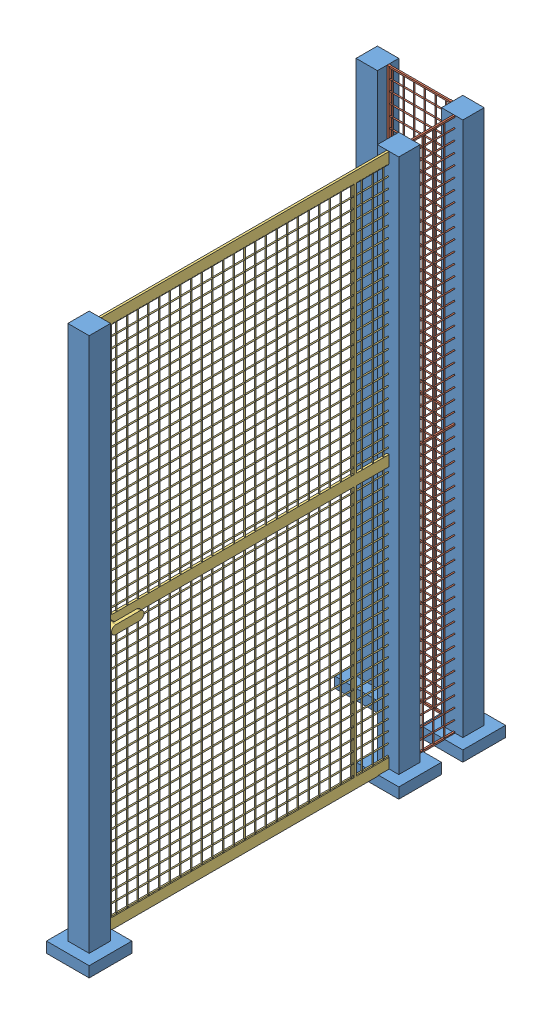
SolidWorks assembly bariera_porta_angolo, configuration Default. Lengths in mm.
Overall size (600 2555 1950).
7 component instances, 3 part files, 19 mates.
Components (placement in the parent):
- palo_barriera-1: palo_barriera [Default] at origin size (200 2555 200)
- palo_barriera-2: palo_barriera [Default] at (0 0 1750) size (200 2555 200)
- palo_barriera-3: palo_barriera [Default] at (0 0 300) size (200 2555 200)
- palo_barriera-4: palo_barriera [Default] at (-400 0 0) size (200 2555 200)
- rete 300-1: rete 300 [Default] at (-77.5 2551.25 0) x (-1 0 0) z (0 -1 0) size (300 10 2507.5)
- rete 300-2: rete 300 [Default] at (10 51.249 297.5) x (0 0 -1) z (0 1 0) size (300 10 2507.5)
- rete2m-1: rete2m [Default] at (0 51.25 1672.5) x (0 0 -1) z (0 1 0) size (1350 55 2507.5)
Mates (geometry in assembly coordinates):
- Coincidente1: coordinate: point of palo_barriera-1
- Distanza1: distance = 1750 mm aligned: plane of palo_barriera-1 through (0 0 0) normal (0 0 1); plane of palo_barriera-2 through (0 0 1750) normal (0 0 1)
- Coincidente3: coincident aligned: plane of palo_barriera-1 through (-50 2550 -50) normal (-1 0 0); plane of palo_barriera-2 through (-50 2550 1700) normal (-1 0 0)
- Coincidente4: coincident aligned: plane of palo_barriera-1 through (0 2555 0) normal (0 1 0); plane of palo_barriera-2 through (0 2555 1750) normal (0 1 0)
- Coincidente5: coincident aligned: plane of palo_barriera-1 through (50 2550 -50) normal (1 0 0); plane of palo_barriera-3 through (50 2550 250) normal (1 0 0)
- Coincidente6: coincident aligned: plane of palo_barriera-1 through (0 2555 0) normal (0 1 0); plane of palo_barriera-3 through (0 2555 300) normal (0 1 0)
- Distanza2: distance = 300 mm aligned: plane of palo_barriera-1 through (0 0 0) normal (0 0 1); plane of palo_barriera-3 through (0 0 300) normal (0 0 1)
- Coincidente8: coincident aligned: plane of palo_barriera-1 through (0 2555 0) normal (0 1 0); plane of palo_barriera-4 through (-400 2555 0) normal (0 1 0)
- Coincidente9: coincident aligned: plane of palo_barriera-1 through (-50 2550 -50) normal (0 0 -1); plane of palo_barriera-4 through (-450 2550 -50) normal (0 0 -1)
- Distanza4: distance = 400 mm aligned: plane of palo_barriera-4 through (-400 0 0) normal (1 0 0); plane of palo_barriera-1 through (0 0 0) normal (1 0 0)
- Coincidente12: coincident aligned: plane of palo_barriera-1 through (0 2555 0) normal (0 1 0); plane of rete 300-1 through (-1010.6066 2555 -3.75) normal (0 1 0)
- Distanza5: distance = 45 mm aligned: plane of rete 300-1 through (-340 2569.1421 -5) normal (0 0 -1); plane of palo_barriera-4 through (-450 2550 -50) normal (0 0 -1)
- Coincidente14: coincident anti-aligned: plane of palo_barriera-4 through (-350 2550 -50) normal (1 0 0); plane of rete 300-1 through (-350 3232.2262 -24.5677) normal (-1 0 0)
- Distanza7: distance = 45 mm anti-aligned: plane of palo_barriera-3 through (50 2550 250) normal (1 0 0); plane of rete 300-2 through (5 33.3569 35) normal (-1 0 0)
- Distanza6: distance = 25 mm anti-aligned: plane of palo_barriera-1 through (-50 2550 50) normal (0 0 1); plane of rete 300-2 through (-14.5677 -629.7272 25) normal (0 0 -1)
- Distanza8: distance = 0.001 mm aligned: plane of palo_barriera-3 through (0 2555 300) normal (0 1 0); plane of rete 300-2 through (6.25 2554.999 -635.6066) normal (0 1 0)
- Coincidente18: coincident anti-aligned: plane of palo_barriera-3 through (-50 2550 350) normal (0 0 1); plane of rete2m-1 through (-171.1689 41.25 350) normal (0 0 -1)
- Coincidente19: coincident aligned: plane of palo_barriera-3 through (0 2555 300) normal (0 1 0); plane of rete2m-1 through (-3.75 2555 -710.6066) normal (0 1 0)
- Distanza9: distance = 45 mm aligned: plane of rete2m-1 through (5 2569.1421 1700) normal (1 0 0); plane of palo_barriera-3 through (50 2550 250) normal (1 0 0)
